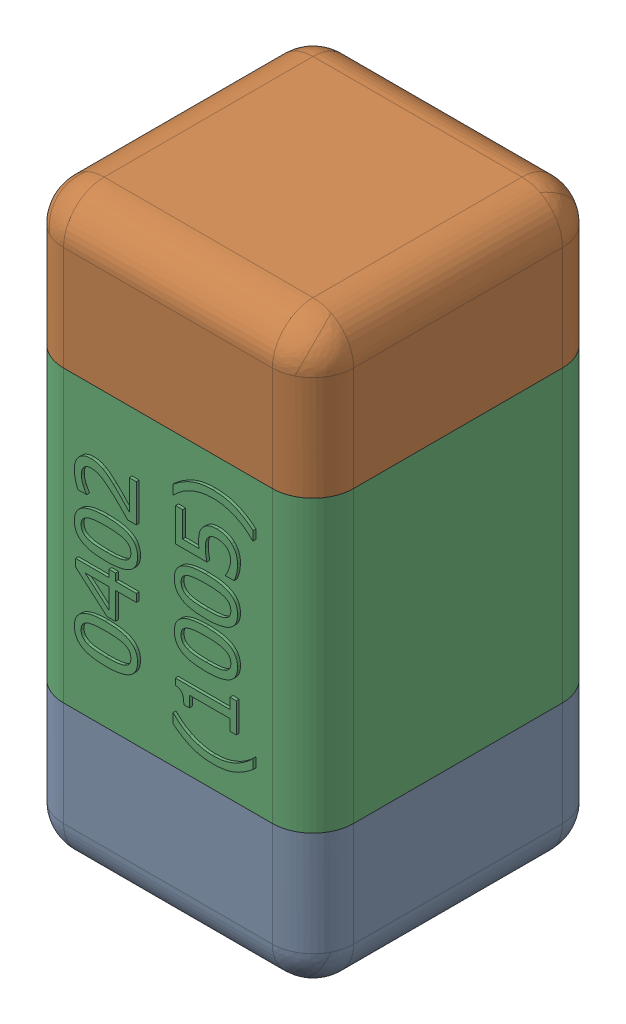
SolidWorks assembly C44, configuration Standard. Lengths in mm.
Overall size (0.51 1.01 0.51).
4 component instances, 3 part files, 0 mates.
Components (placement in the parent):
- C44-subassembly-1-1: C44-subassembly-1 [Standard] at (-8.7 9.1001 0) x (0 1 0) z (0 0 1) size (1.01 0.51 0.51)
  - User Library-0402_Cap-1: User Library-0402_Cap [Standard] at origin size (0.26 0.51 0.51)
  - User Library-0402_Cap-1-1: User Library-0402_Cap-1 [Standard] at origin size (0.26 0.5 0.51)
  - User Library-0402_Cap-2-1: User Library-0402_Cap-2 [Standard] at origin size (0.5 0.5 0.51)
